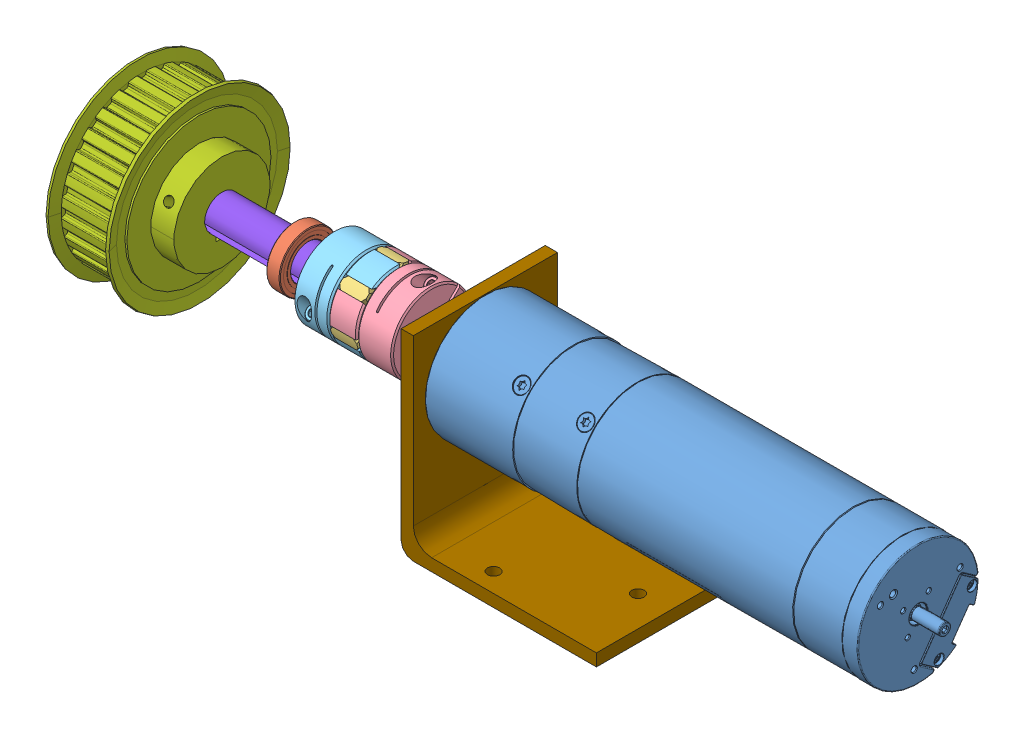
SolidWorks assembly motor assm3, configuration Default. Lengths in mm.
Overall size (425.18 125.29 110.59).
13 component instances, 10 part files, 16 mates.
Components (placement in the parent):
- motor v1-1: motor v1 [Default] at (-10.682 -30.4372 60.8855) x (1 0 0) z (0 -0.707107 0.707107) size (278.16 78.2 78.2)
- vbx_18mmID_bearing-1: vbx_18mmID_bearing [5972K329] at (-101.2086 -30.4372 60.8855) x (0 0 1) z (1 0 0) size (30 30 7)
- 15-18mm Misalinemnt coupler-1: 15-18mm Misalinemnt coupler [Default] at (-34.8408 -36.8901 34.1182) x (0 -0.707107 0.707107) z (-1 0 0) size (41.3 42.02 51.03)
  - 9845T210_VIBRATE-DAMPING PRECISION FLEXIBLE SHAFT CPLG-1: 9845T210_VIBRATE-DAMPING PRECISION FLEXIBLE SHAFT CPLG [9845T21] at (14.3644 23.4902 31.8678) size (38.38 42 16.93)
  - 9845T469_VIBRATE-DAMPING PRECISION FLEXIBLE SHAFT COUPLING-1: 9845T469_VIBRATE-DAMPING PRECISION FLEXIBLE SHAFT COUPLING [9845T469] at (14.3644 23.4902 25.3411) size (41.3 41.3 33.46)
  - 9845T471_VIBRATE-DAMPING PRECISION FLEXIBLE SHAFT COUPLING-1: 9845T471_VIBRATE-DAMPING PRECISION FLEXIBLE SHAFT COUPLING [9845T471] at (14.3644 23.4902 23.3678) x (-1 0 0) z (0 0 -1) size (41.3 41.3 33.46)
- Encoder v1-1: Encoder v1 [Default] at (-285.7992 -30.4372 60.8855) x (0 -0.379337 0.925259) z (-1 0 0) size (50.8 52.34 36.53) (hidden)
- 28tooth-1: 28tooth [Default] at (-186.7086 -30.4372 60.8855) x (1 0 0) z (0 0 -1) size (44.41 95 95)
  - ATPA28L100_B_N18_3-1: ATPA28L100_B_N18_3 [Default] at (38 -4.5 -7.7942) x (0 0.5 0.866025) z (-1 0 0) size (5 6 6)
  - ATPA28L100_B_N18_3-2: ATPA28L100_B_N18_3 [Default] at (38 11.8 0) x (0 -1 0) z (-1 0 0) size (5 6 6)
  - ATPA28L100_B_N18_6-1: ATPA28L100_B_N18_6 [Default] at origin size (44.41 95 95)
- 1439K370_1045 CARBON STEEL KEYED ROTARY SHAFT_editied-1: 1439K370_1045 CARBON STEEL KEYED ROTARY SHAFT_editied [1439K37] at (-129.2086 -30.4372 60.8855) x (0 0.910266 0.414024) z (1 0 0) size (18 17.49 125)
- Motor mount-1: Motor mount [Default] at (-12.032 -100.4372 23.3855) x (0 0 1) z (-1 0 0) size (75 101.6 101.89)
Mates (geometry in assembly coordinates):
- Concentric25: concentric anti-aligned: cylinder of vbx_18mmID_bearing-1 through (-97.7086 -30.4372 60.8855) axis (1 0 0) radius 9; cylinder of 1439K611_1045 CARBON STEEL KEYED ROTARY SHAFT (1)-1 through (-34.75 0 0) axis (-1 0 0) radius 10
- Parallel10: parallel anti-aligned: plane of vbx_18mmID_bearing-1 through (-101.2086 -30.4372 60.8855) normal (0 -1 0); plane of 1439K611_1045 CARBON STEEL KEYED ROTARY SHAFT (1)-1 through (-334.75 -3 10) normal (0 1 0)
- Concentric26: concentric anti-aligned: cylinder of 1439K611_1045 CARBON STEEL KEYED ROTARY SHAFT (1)-1 through (-34.75 0 0) axis (-1 0 0) radius 10; cylinder of timming belt pully-1/timing belt pully face-2 through (-119.9209 0 0) axis (1 0 0) radius 10
- Parallel12: parallel anti-aligned: plane of 1439K611_1045 CARBON STEEL KEYED ROTARY SHAFT (1)-1 through (-334.75 -3 10) normal (0 1 0); plane of timming belt pully-1/timing belt pully face-1 through (-158.0209 -2.95 0) normal (0 -1 0)
- Concentric50: concentric anti-aligned: cylinder of motor v1-1 through (-15.882 -30.4372 60.8855) axis (-1 0 0) radius 7.5; cylinder of 15-18mm Misalinemnt coupler-1/9845T469_VIBRATE-DAMPING PRECISION FLEXIBLE SHAFT COUPLING-1 through (-78.682 -30.4372 60.8855) axis (1 0 0) radius 7.5
- Coincident48: coincident anti-aligned: plane of motor v1-1 through (-39.182 -37.5082 64.421) normal (0 -0.707107 -0.707107); plane of 15-18mm Misalinemnt coupler-1/9845T469_VIBRATE-DAMPING PRECISION FLEXIBLE SHAFT COUPLING-1 through (-33.682 -38.0739 64.9867) normal (0 0.707107 0.707107)
- Coincident49: coincident aligned: plane of 15-18mm Misalinemnt coupler-1/9845T469_VIBRATE-DAMPING PRECISION FLEXIBLE SHAFT COUPLING-1 through (-44.682 -30.4372 31.682) normal (-1 0 0); plane of motor v1-1 through (-44.682 -27.7502 63.5725) normal (-1 0 0)
- Concentric55: concentric anti-aligned: cylinder of vbx_18mmID_bearing-1 through (-97.7086 -30.4372 60.8855) axis (1 0 0) radius 9; cylinder of Encoder v1-1 through (-261.0342 -30.4372 60.8855) axis (-1 0 0) radius 7.5006
- Concentric61: concentric anti-aligned: cylinder of vbx_18mmID_bearing-1 through (-97.7086 -30.4372 60.8855) axis (1 0 0) radius 9; cylinder of 1439K370_1045 CARBON STEEL KEYED ROTARY SHAFT_editied-1 through (-66.7086 -30.4372 60.8855) axis (-1 0 0) radius 9
- Concentric62: concentric anti-aligned: cylinder of 28tooth-1/ATPA28L100_B_N18_6-1 through (-142.7086 -30.4372 60.8855) axis (1 0 0) radius 9; cylinder of 1439K370_1045 CARBON STEEL KEYED ROTARY SHAFT_editied-1 through (-66.7086 -30.4372 60.8855) axis (-1 0 0) radius 9
- Distance5: distance = 5 mm aligned: plane of 28tooth-1/ATPA28L100_B_N18_6-1 through (-186.7086 -30.4372 60.8855) normal (-1 0 0); plane of 1439K370_1045 CARBON STEEL KEYED ROTARY SHAFT_editied-1 through (-191.7086 -30.4372 60.8855) normal (-1 0 0)
- Concentric64: concentric anti-aligned: cylinder of motor v1-1 through (-7.932 -30.4372 60.8855) axis (1 0 0) radius 20; cylinder of Motor mount-1 through (62.968 -30.4372 60.8855) axis (-1 0 0) radius 21
- Coincident50: coincident anti-aligned: plane of motor v1-1 through (-5.682 -48.6452 79.0935) normal (-1 0 0); plane of Motor mount-1 through (-5.682 1.1628 98.3855) normal (1 0 0)
- Concentric65: concentric aligned: cylinder of motor v1-1 through (0.818 -12.0524 42.5007) axis (-1 0 0) radius 2.067; cylinder of Motor mount-1 through (-12.032 -12.0524 42.5007) axis (-1 0 0) radius 2.65
- Coincident53: coincident aligned: plane of 15-18mm Misalinemnt coupler-1/9845T471_VIBRATE-DAMPING PRECISION FLEXIBLE SHAFT COUPLING-1 through (-66.7086 -30.4372 60.8855) normal (1 0 0); plane of 1439K370_1045 CARBON STEEL KEYED ROTARY SHAFT_editied-1 through (-66.7086 -30.4372 60.8855) normal (1 0 0)
- Distance7: distance = 45 mm aligned: plane of 28tooth-1/ATPA28L100_B_N18_6-1 through (-142.7086 -55.4372 60.8855) normal (1 0 0); plane of vbx_18mmID_bearing-1 through (-97.7086 -45.0872 60.8855) normal (1 0 0)
